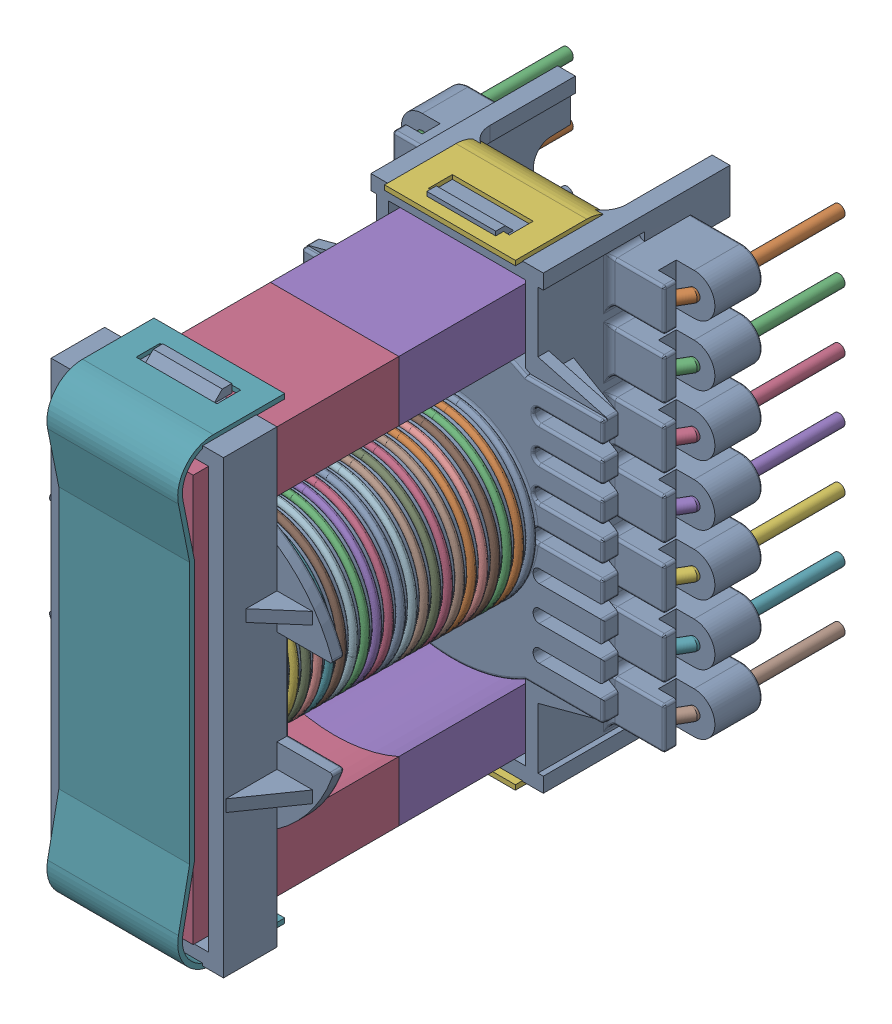
SolidWorks assembly L1, configuration Default. Lengths in mm.
Overall size (26.36 39.3 49.7).
22 component instances, 5 part files, 0 mates.
Components (placement in the parent):
- ETD_34_Vertical-1: ETD_34_Vertical [Default] at (126.0623 118.0749 0) x (0 1 0) z (1 0 0) size (39.3 49.7 26.36)
  - User_Library-ETD34-17-11_Vertical_Bobbin_Part_No._FD9640-1: User_Library-ETD34-17-11_Vertical_Bobbin_Part_No._FD9640 [Default] at (-19.65 26.6 -12.65) x (-1 0 0) z (0 0 1) size (39.3 49.7 26.36)
    - User_Library-ETD34-17-11_Vertical_Bobbin_Part_No._FD9640_FD9640-1: User_Library-ETD34-17-11_Vertical_Bobbin_Part_No._FD9640_FD9640 [Default] at origin size (39.3 42.6 26.36)
    - User_Library-ETD34-17-11_Vertical_Bobbin_Part_No._FD9640_1MM_RND_PIN-1: User_Library-ETD34-17-11_Vertical_Bobbin_Part_No._FD9640_1MM_RND_PIN [Default] at origin size (1 13.75 1.63)
    - User_Library-ETD34-17-11_Vertical_Bobbin_Part_No._FD9640_1MM_RND_PIN-2: User_Library-ETD34-17-11_Vertical_Bobbin_Part_No._FD9640_1MM_RND_PIN [Default] at (5.08 0 0) size (1 13.75 1.63)
    - User_Library-ETD34-17-11_Vertical_Bobbin_Part_No._FD9640_1MM_RND_PIN-3: User_Library-ETD34-17-11_Vertical_Bobbin_Part_No._FD9640_1MM_RND_PIN [Default] at (10.16 0 0) size (1 13.75 1.63)
    - User_Library-ETD34-17-11_Vertical_Bobbin_Part_No._FD9640_1MM_RND_PIN-4: User_Library-ETD34-17-11_Vertical_Bobbin_Part_No._FD9640_1MM_RND_PIN [Default] at (15.24 0 0) size (1 13.75 1.63)
    - User_Library-ETD34-17-11_Vertical_Bobbin_Part_No._FD9640_1MM_RND_PIN-5: User_Library-ETD34-17-11_Vertical_Bobbin_Part_No._FD9640_1MM_RND_PIN [Default] at (20.32 0 0) size (1 13.75 1.63)
    - User_Library-ETD34-17-11_Vertical_Bobbin_Part_No._FD9640_1MM_RND_PIN-6: User_Library-ETD34-17-11_Vertical_Bobbin_Part_No._FD9640_1MM_RND_PIN [Default] at (25.4 0 0) size (1 13.75 1.63)
    - User_Library-ETD34-17-11_Vertical_Bobbin_Part_No._FD9640_1MM_RND_PIN-7: User_Library-ETD34-17-11_Vertical_Bobbin_Part_No._FD9640_1MM_RND_PIN [Default] at (30.48 0 0) size (1 13.75 1.63)
    - User_Library-ETD34-17-11_Vertical_Bobbin_Part_No._FD9640_1MM_RND_PIN-8: User_Library-ETD34-17-11_Vertical_Bobbin_Part_No._FD9640_1MM_RND_PIN [Default] x (-1 0 0) z (0 0 -1) size (1 13.75 1.63)
    - User_Library-ETD34-17-11_Vertical_Bobbin_Part_No._FD9640_1MM_RND_PIN-9: User_Library-ETD34-17-11_Vertical_Bobbin_Part_No._FD9640_1MM_RND_PIN [Default] at (-5.08 0 0) x (-1 0 0) z (0 0 -1) size (1 13.75 1.63)
    - User_Library-ETD34-17-11_Vertical_Bobbin_Part_No._FD9640_1MM_RND_PIN-10: User_Library-ETD34-17-11_Vertical_Bobbin_Part_No._FD9640_1MM_RND_PIN [Default] at (-10.16 0 0) x (-1 0 0) z (0 0 -1) size (1 13.75 1.63)
    - User_Library-ETD34-17-11_Vertical_Bobbin_Part_No._FD9640_1MM_RND_PIN-11: User_Library-ETD34-17-11_Vertical_Bobbin_Part_No._FD9640_1MM_RND_PIN [Default] at (-15.24 0 0) x (-1 0 0) z (0 0 -1) size (1 13.75 1.63)
    - User_Library-ETD34-17-11_Vertical_Bobbin_Part_No._FD9640_1MM_RND_PIN-12: User_Library-ETD34-17-11_Vertical_Bobbin_Part_No._FD9640_1MM_RND_PIN [Default] at (-20.32 0 0) x (-1 0 0) z (0 0 -1) size (1 13.75 1.63)
    - User_Library-ETD34-17-11_Vertical_Bobbin_Part_No._FD9640_1MM_RND_PIN-13: User_Library-ETD34-17-11_Vertical_Bobbin_Part_No._FD9640_1MM_RND_PIN [Default] at (-25.4 0 0) x (-1 0 0) z (0 0 -1) size (1 13.75 1.63)
    - User_Library-ETD34-17-11_Vertical_Bobbin_Part_No._FD9640_1MM_RND_PIN-14: User_Library-ETD34-17-11_Vertical_Bobbin_Part_No._FD9640_1MM_RND_PIN [Default] at (-30.48 0 0) x (-1 0 0) z (0 0 -1) size (1 13.75 1.63)
    - User_Library-ETD34-17-11_Vertical_Bobbin_Part_No._FD9640_ETD34_CORE-1: User_Library-ETD34-17-11_Vertical_Bobbin_Part_No._FD9640_ETD34_CORE [Default] at (0 -16.7 0) size (34.2 17.3 10.8)
    - User_Library-ETD34-17-11_Vertical_Bobbin_Part_No._FD9640_ETD34_CORE-2: User_Library-ETD34-17-11_Vertical_Bobbin_Part_No._FD9640_ETD34_CORE [Default] at (0 17.9 0) x (-1 0 0) z (0 0 1) size (34.2 17.3 10.8)
    - User_Library-ETD34-17-11_Vertical_Bobbin_Part_No._FD9640_ETD34_CORE_CLIP-1: User_Library-ETD34-17-11_Vertical_Bobbin_Part_No._FD9640_ETD34_CORE_CLIP [Default] at (0 10.3 -5.5) x (0 -1 0) z (-1 0 0) size (9 11 38.6)
    - User_Library-ETD34-17-11_Vertical_Bobbin_Part_No._FD9640_ETD34_CORE_CLIP-2: User_Library-ETD34-17-11_Vertical_Bobbin_Part_No._FD9640_ETD34_CORE_CLIP [Default] at (0 -9.1 5.5) x (0 1 0) z (-1 0 0) size (9 11 38.6)
    - User_Library-ETD34-17-11_Vertical_Bobbin_Part_No._FD9640_ETD34_WINDING-1: User_Library-ETD34-17-11_Vertical_Bobbin_Part_No._FD9640_ETD34_WINDING [Default] at (0.2458 10.0424 -0.0108) x (-0.015539 -0.999863 0.005636) z (0.990175 -0.016171 -0.138898) size (20.6 14.6 14.6)
